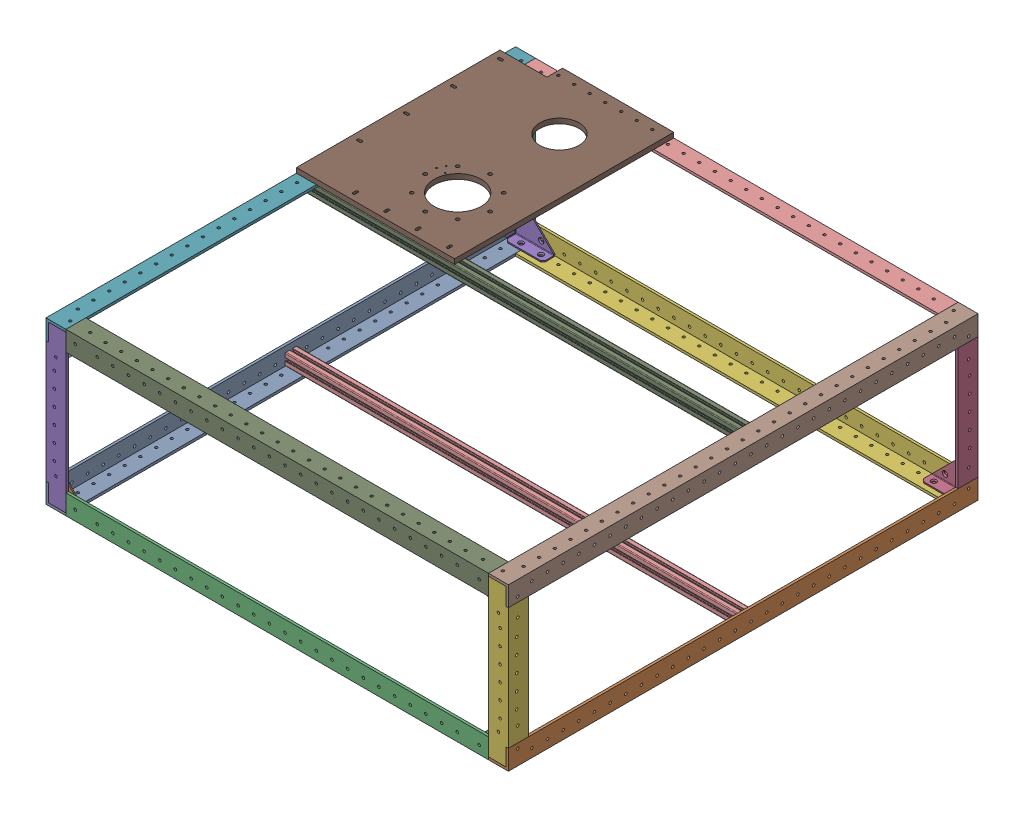
SolidWorks assembly URC Frame Assembly 2025-2023, configuration Default. Lengths in mm.
Overall size (590.8 212.69 600).
23 component instances, 6 part files, 91 mates.
Components (placement in the parent):
- 600mm L Angle 0.125 in-2023-2: 600mm L Angle 0.125 in-2023 [8982K421] at (-25.1001 123.5857 -689.9173) size (25.4 25.4 600)
- 600mm L Angle 0.125 in-2023-3: 600mm L Angle 0.125 in-2023 [8982K421] at (565.6999 123.5807 1148.4827) x (-1 0 0) z (0 0 -1) size (25.4 25.4 600)
- 200mm L Angle 0.125 in-2023-1: 200mm L Angle 0.125 in-2023 [8982K421] at (-25.1001 -892.4443 -70.7173) x (0 0 1) z (0 1 0) size (25.4 25.4 200)
- 200mm L Angle 0.125 in-2023-2: 200mm L Angle 0.125 in-2023 [8982K421] at (565.6999 1345.9557 -70.7173) x (0 0 1) z (0 -1 0) size (25.4 25.4 200)
- 200mm L Angle 0.125 in-2023-3: 200mm L Angle 0.125 in-2023 [8982K421] at (-25.1001 1345.9607 529.2827) x (0 0 -1) z (0 -1 0) size (25.4 25.4 200)
- 200mm L Angle 0.125 in-2023-4: 200mm L Angle 0.125 in-2023 [8982K421] at (565.6999 -892.4443 529.2827) x (0 0 -1) z (0 1 0) size (25.4 25.4 200)
- 600mm L Angle 0.125 in-2023-5: 600mm L Angle 0.125 in-2023 [8982K421] at (-25.1001 329.9257 -689.9173) x (0 -1 0) z (0 0 1) size (25.4 25.4 600)
- 600mm L Angle 0.125 in-2023-6: 600mm L Angle 0.125 in-2023 [8982K421] at (565.6999 329.9257 -689.9173) x (-1 0 0) z (0 0 1) size (25.4 25.4 600)
- 584 mm L Angle 0.125 in-2023-5: 584 mm L Angle 0.125 in-2023 [8982K421] at (-678.9001 329.9257 529.2827) x (0 -1 0) z (1 0 0) size (25.4 25.4 540)
- 584 mm L Angle 0.125 in-2023-6: 584 mm L Angle 0.125 in-2023 [8982K421] at (1219.4999 329.9257 -70.7173) x (0 -1 0) z (-1 0 0) size (25.4 25.4 540)
- 1088A31_Inside-Corner Reinforcing Bracket-2023-1: 1088A31_Inside-Corner Reinforcing Bracket-2023 [1088A31] at (562.5249 326.7507 524.5837) x (-1 0 0) z (0 -1 0) size (50.93 15.88 50.93)
- 1088A31_Inside-Corner Reinforcing Bracket-2023-2: 1088A31_Inside-Corner Reinforcing Bracket-2023 [1088A31] at (-21.9251 326.7507 524.5837) x (0 -1 0) z (1 0 0) size (50.93 15.88 50.93)
- 1088A31_Inside-Corner Reinforcing Bracket-2023-3: 1088A31_Inside-Corner Reinforcing Bracket-2023 [1088A31] at (562.5249 126.7557 524.5837) x (0 1 0) z (-1 0 0) size (50.93 15.88 50.93)
- 1088A31_Inside-Corner Reinforcing Bracket-2023-4: 1088A31_Inside-Corner Reinforcing Bracket-2023 [1088A31] at (-21.9251 126.7607 524.5837) x (1 0 0) z (0 1 0) size (50.93 15.88 50.93)
- 584 mm L Angle 0.125 in-2023-7: 584 mm L Angle 0.125 in-2023 [8982K421] at (1219.4999 123.5807 529.2827) x (0 1 0) z (-1 0 0) size (25.4 25.4 540)
- 1088A31_Inside-Corner Reinforcing Bracket-2023-5: 1088A31_Inside-Corner Reinforcing Bracket-2023 [1088A31] at (562.5249 126.7607 -66.0183) x (-1 0 0) z (0 1 0) size (50.93 15.88 50.93)
- 1088A31_Inside-Corner Reinforcing Bracket-2023-6: 1088A31_Inside-Corner Reinforcing Bracket-2023 [1088A31] at (-21.9251 126.7607 -66.0183) x (0 1 0) z (1 0 0) size (50.93 15.88 50.93)
- 584 mm L Angle 0.125 in-2023-9: 584 mm L Angle 0.125 in-2023 [8982K421] at (-678.9001 123.5857 -70.7173) x (0 1 0) z (1 0 0) size (25.4 25.4 540)
- 1088A31_Inside-Corner Reinforcing Bracket-2023-7: 1088A31_Inside-Corner Reinforcing Bracket-2023 [1088A31] at (562.5249 326.7507 -66.0183) x (0 -1 0) z (-1 0 0) size (50.93 15.88 50.93)
- 1088A31_Inside-Corner Reinforcing Bracket-2023-8: 1088A31_Inside-Corner Reinforcing Bracket-2023 [1088A31] at (-21.9251 326.7507 -66.0183) x (1 0 0) z (0 -1 0) size (50.93 15.88 50.93)
- T Slot Extrusion-2023-1: T Slot Extrusion-2023 [Default] at (92.5749 319.2507 199.2827) x (0 0 1) z (-1 0 0) size (15 15 584.45)
- T Slot Extrusion-2023-2: T Slot Extrusion-2023 [Default] at (92.5749 134.2607 219.2827) x (0 0 1) z (-1 0 0) size (15 15 584.45)
- 2025 Arm Plate-2023-1: 2025 Arm Plate-2023 [Default] at (105.8999 329.9257 69.2827) size (202 6.35 280)
Mates (geometry in assembly coordinates):
- Coincident10: coincident anti-aligned: plane of 600mm L Angle 0.125 in-2 through (0.2999 123.5857 529.2827) normal (1 0 0); plane of 584 mm L Angle 0.125 in-3 through (0.2999 123.5857 -70.7173) normal (-1 0 0)
- Coincident11: coincident aligned: plane of 600mm L Angle 0.125 in-2 through (0.2999 126.7607 529.2827) normal (0 1 0); plane of 584 mm L Angle 0.125 in-3 through (0.2999 126.7607 -45.3173) normal (0 1 0)
- Coincident12: coincident aligned: plane of 600mm L Angle 0.125 in-2 through (34.8999 148.9857 -70.7173) normal (0 0 -1); plane of 584 mm L Angle 0.125 in-3 through (0.2999 148.9857 -70.7173) normal (0 0 -1)
- Coincident16: coincident aligned: plane of 584 mm L Angle 0.125 in-3 through (0.2999 126.7607 -45.3173) normal (0 1 0); plane of 600mm L Angle 0.125 in-3 through (540.2999 126.7557 -70.7173) normal (0 1 0)
- Coincident17: coincident anti-aligned: plane of 584 mm L Angle 0.125 in-3 through (540.2999 148.9857 -10.7173) normal (1 0 0); plane of 600mm L Angle 0.125 in-3 through (540.2999 123.5807 -70.7173) normal (-1 0 0)
- Coincident18: coincident aligned: plane of 584 mm L Angle 0.125 in-3 through (0.2999 148.9857 -70.7173) normal (0 0 -1); plane of 600mm L Angle 0.125 in-3 through (565.6999 123.5807 -70.7173) normal (0 0 -1)
- Coincident19: coincident anti-aligned: plane of 600mm L Angle 0.125 in-3 through (540.2999 123.5807 -70.7173) normal (-1 0 0); plane of 584 mm L Angle 0.125 in-4 through (540.2999 123.5857 529.2827) normal (1 0 0)
- Coincident20: coincident aligned: plane of 600mm L Angle 0.125 in-3 through (540.2999 126.7557 -70.7173) normal (0 1 0); plane of 584 mm L Angle 0.125 in-4 through (540.2999 126.7607 503.8827) normal (0 1 0)
- Coincident21: coincident aligned: plane of 600mm L Angle 0.125 in-2 through (-25.1001 123.5857 529.2827) normal (0 0 1); plane of 584 mm L Angle 0.125 in-4 through (540.2999 148.9857 529.2827) normal (0 0 1)
- Coincident22: coincident aligned: plane of 600mm L Angle 0.125 in-2 through (-25.1001 148.9857 529.2827) normal (-1 0 0); plane of 200mm L Angle 0.125 in-1 through (-25.1001 326.7557 -70.7173) normal (-1 0 0)
- Coincident23: coincident aligned: plane of 584 mm L Angle 0.125 in-3 through (0.2999 148.9857 -70.7173) normal (0 0 -1); plane of 200mm L Angle 0.125 in-1 through (0.2999 326.7557 -70.7173) normal (0 0 -1)
- Coincident24: coincident anti-aligned: plane of 600mm L Angle 0.125 in-2 through (-21.9251 148.9857 529.2827) normal (0 1 0); plane of 200mm L Angle 0.125 in-1 through (11.8289 148.9857 -45.3173) normal (0 -1 0)
- Coincident25: coincident anti-aligned: plane of 600mm L Angle 0.125 in-3 through (540.2999 126.7557 -70.7173) normal (0 1 0); plane of 200mm L Angle 0.125 in-2 through (565.6999 126.7557 -70.7173) normal (0 -1 0)
- Coincident26: coincident aligned: plane of 584 mm L Angle 0.125 in-3 through (0.2999 148.9857 -70.7173) normal (0 0 -1); plane of 200mm L Angle 0.125 in-2 through (540.2999 126.7557 -70.7173) normal (0 0 -1)
- Coincident27: coincident aligned: plane of 600mm L Angle 0.125 in-3 through (565.6999 148.9807 -70.7173) normal (1 0 0); plane of 200mm L Angle 0.125 in-2 through (565.6999 126.7557 -70.7173) normal (1 0 0)
- Coincident28: coincident anti-aligned: plane of 600mm L Angle 0.125 in-2 through (0.2999 126.7607 529.2827) normal (0 1 0); plane of 200mm L Angle 0.125 in-3 through (-25.1001 126.7607 529.2827) normal (0 -1 0)
- Coincident29: coincident aligned: plane of 584 mm L Angle 0.125 in-4 through (540.2999 148.9857 529.2827) normal (0 0 1); plane of 200mm L Angle 0.125 in-3 through (0.2999 126.7607 529.2827) normal (0 0 1)
- Coincident30: coincident aligned: plane of 600mm L Angle 0.125 in-2 through (-25.1001 148.9857 529.2827) normal (-1 0 0); plane of 200mm L Angle 0.125 in-3 through (-25.1001 126.7607 529.2827) normal (-1 0 0)
- Coincident33: coincident anti-aligned: plane of 600mm L Angle 0.125 in-3 through (540.2999 126.7557 -70.7173) normal (0 1 0); plane of 200mm L Angle 0.125 in-4 through (540.2999 126.7557 469.2827) normal (0 -1 0)
- Coincident34: coincident aligned: plane of 584 mm L Angle 0.125 in-4 through (540.2999 148.9857 529.2827) normal (0 0 1); plane of 200mm L Angle 0.125 in-4 through (540.2999 326.7557 529.2827) normal (0 0 1)
- Coincident35: coincident aligned: plane of 600mm L Angle 0.125 in-3 through (565.6999 148.9807 -70.7173) normal (1 0 0); plane of 200mm L Angle 0.125 in-4 through (565.6999 326.7557 529.2827) normal (1 0 0)
- Coincident36: coincident aligned: plane of 200mm L Angle 0.125 in-3 through (-25.1001 126.7607 529.2827) normal (-1 0 0); plane of 600mm L Angle 0.125 in-4 through (-25.1001 129.9357 250.1294) normal (-1 0 0)
- Coincident37: coincident anti-aligned: plane of 600mm L Angle 0.125 in-2 through (0.2999 126.7607 529.2827) normal (0 1 0); plane of 600mm L Angle 0.125 in-4 through (-21.9251 126.7607 250.1294) normal (0 -1 0)
- Coincident39: coincident anti-aligned: plane of 200mm L Angle 0.125 in-1 through (11.8289 304.5257 -45.3173) normal (0 1 0); plane of 600mm L Angle 0.125 in-5 through (-25.1001 304.5257 529.2827) normal (0 -1 0)
- Coincident40: coincident aligned: plane of 200mm L Angle 0.125 in-1 through (0.2999 326.7557 -70.7173) normal (0 0 -1); plane of 600mm L Angle 0.125 in-5 through (0.2999 269.9257 -70.7173) normal (0 0 -1)
- Coincident41: coincident aligned: plane of 200mm L Angle 0.125 in-1 through (-25.1001 326.7557 -70.7173) normal (-1 0 0); plane of 600mm L Angle 0.125 in-5 through (-25.1001 329.9257 529.2827) normal (-1 0 0)
- Coincident42: coincident aligned: plane of 200mm L Angle 0.125 in-4 through (565.6999 326.7557 529.2827) normal (1 0 0); plane of 600mm L Angle 0.125 in-6 through (565.6999 304.5257 529.2827) normal (1 0 0)
- Coincident43: coincident anti-aligned: plane of 200mm L Angle 0.125 in-4 through (528.7709 304.5257 503.8827) normal (0 1 0); plane of 600mm L Angle 0.125 in-6 through (562.5249 304.5257 529.2827) normal (0 -1 0)
- Coincident44: coincident aligned: plane of 200mm L Angle 0.125 in-4 through (540.2999 326.7557 529.2827) normal (0 0 1); plane of 600mm L Angle 0.125 in-6 through (565.6999 329.9257 529.2827) normal (0 0 1)
- Coincident45: coincident anti-aligned: plane of 600mm L Angle 0.125 in-6 through (540.2999 329.9257 529.2827) normal (-1 0 0); plane of 584 mm L Angle 0.125 in-5 through (540.2999 329.9257 529.2827) normal (1 0 0)
- Coincident46: coincident aligned: plane of 200mm L Angle 0.125 in-4 through (540.2999 326.7557 529.2827) normal (0 0 1); plane of 584 mm L Angle 0.125 in-5 through (540.2999 329.9257 529.2827) normal (0 0 1)
- Coincident47: coincident aligned: plane of 600mm L Angle 0.125 in-6 through (565.6999 329.9257 529.2827) normal (0 1 0); plane of 584 mm L Angle 0.125 in-5 through (540.2999 329.9257 503.8827) normal (0 1 0)
- Coincident48: coincident aligned: plane of 200mm L Angle 0.125 in-2 through (540.2999 126.7557 -70.7173) normal (0 0 -1); plane of 584 mm L Angle 0.125 in-6 through (0.2999 329.9257 -70.7173) normal (0 0 -1)
- Coincident49: coincident aligned: plane of 600mm L Angle 0.125 in-6 through (565.6999 329.9257 529.2827) normal (0 1 0); plane of 584 mm L Angle 0.125 in-6 through (0.2999 329.9257 -45.3173) normal (0 1 0)
- Coincident50: coincident anti-aligned: plane of 600mm L Angle 0.125 in-5 through (0.2999 326.7507 529.2827) normal (1 0 0); plane of 584 mm L Angle 0.125 in-6 through (0.2999 329.9257 -70.7173) normal (-1 0 0)
- Concentric1: concentric aligned: circle of 600mm L Angle 0.125 in-6; circle of 1088A31_Inside-Corner Reinforcing Bracket-1
- Parallel2: parallel aligned: plane of 200mm L Angle 0.125 in-4 through (565.6999 326.7557 503.8827) normal (0 0 -1); plane of 1088A31_Inside-Corner Reinforcing Bracket-1 through (562.5249 325.2267 510.2327) normal (0 0 -1)
- Coincident52: coincident anti-aligned: plane of 200mm L Angle 0.125 in-4 through (562.5249 326.7557 503.8827) normal (-1 0 0); plane of 1088A31_Inside-Corner Reinforcing Bracket-1 through (562.5249 275.9507 524.5837) normal (1 0 0)
- Concentric2: concentric anti-aligned: circle of 600mm L Angle 0.125 in-5; circle of 1088A31_Inside-Corner Reinforcing Bracket-2
- Coincident53: coincident anti-aligned: plane of 200mm L Angle 0.125 in-3 through (-21.9251 126.7607 526.1077) normal (0 0 -1); plane of 1088A31_Inside-Corner Reinforcing Bracket-2 through (-20.4011 325.2267 526.1077) normal (0 0 1)
- Coincident54: coincident anti-aligned: plane of 600mm L Angle 0.125 in-5 through (-21.9251 304.5257 529.2827) normal (1 0 0); plane of 1088A31_Inside-Corner Reinforcing Bracket-2 through (-21.9251 275.9507 510.2327) normal (-1 0 0)
- Coincident55: coincident anti-aligned: plane of 200mm L Angle 0.125 in-4 through (562.5249 326.7557 503.8827) normal (-1 0 0); plane of 1088A31_Inside-Corner Reinforcing Bracket-3 through (562.5249 177.5557 510.2327) normal (1 0 0)
- Coincident56: coincident anti-aligned: plane of 200mm L Angle 0.125 in-4 through (562.5249 326.7557 526.1077) normal (0 0 -1); plane of 1088A31_Inside-Corner Reinforcing Bracket-3 through (561.0009 128.2797 526.1077) normal (0 0 1)
- Coincident57: coincident anti-aligned: plane of 600mm L Angle 0.125 in-3 through (540.2999 126.7557 -70.7173) normal (0 1 0); plane of 1088A31_Inside-Corner Reinforcing Bracket-3 through (511.7249 126.7557 524.5837) normal (0 -1 0)
- Coincident58: coincident anti-aligned: plane of 600mm L Angle 0.125 in-2 through (0.2999 126.7607 529.2827) normal (0 1 0); plane of 1088A31_Inside-Corner Reinforcing Bracket-4 through (28.8749 126.7607 510.2327) normal (0 -1 0)
- Coincident59: coincident anti-aligned: plane of 200mm L Angle 0.125 in-3 through (-21.9251 126.7607 526.1077) normal (0 0 -1); plane of 1088A31_Inside-Corner Reinforcing Bracket-4 through (-20.4011 128.2847 526.1077) normal (0 0 1)
- Coincident60: coincident anti-aligned: plane of 200mm L Angle 0.125 in-3 through (-21.9251 126.7607 503.8827) normal (1 0 0); plane of 1088A31_Inside-Corner Reinforcing Bracket-4 through (-21.9251 177.5607 524.5837) normal (-1 0 0)
- Coincident61: coincident aligned: plane of 600mm L Angle 0.125 in-3 through (565.6999 123.5807 -70.7173) normal (0 -1 0); plane of 584 mm L Angle 0.125 in-7 through (0.2999 123.5807 503.8827) normal (0 -1 0)
- Coincident62: coincident aligned: plane of 200mm L Angle 0.125 in-4 through (540.2999 326.7557 529.2827) normal (0 0 1); plane of 584 mm L Angle 0.125 in-7 through (0.2999 123.5807 529.2827) normal (0 0 1)
- Coincident64: coincident anti-aligned: plane of 600mm L Angle 0.125 in-3 through (540.2999 123.5807 -70.7173) normal (-1 0 0); plane of 584 mm L Angle 0.125 in-7 through (540.2999 183.5807 503.8827) normal (1 0 0)
- Coincident65: coincident aligned: plane of 200mm L Angle 0.125 in-2 through (540.2999 126.7557 -70.7173) normal (0 0 -1); plane of 600mm L Angle 0.125 in-6 through (505.6999 304.5257 -70.7173) normal (0 0 -1)
- Coincident66: coincident: plane of 584 mm L Angle 0.125 in-3 through (0.2999 126.7607 -45.3173) normal (0 1 0); plane of 1088A31_Inside-Corner Reinforcing Bracket-5 through (511.7249 126.7607 -51.6673) normal (0 -1 0)
- Coincident67: coincident: plane of 584 mm L Angle 0.125 in-3 through (0.2999 126.7607 -67.5423) normal (0 0 1); plane of 1088A31_Inside-Corner Reinforcing Bracket-5 through (561.0009 128.2847 -67.5423) normal (0 0 -1)
- Coincident68: coincident anti-aligned: plane of 200mm L Angle 0.125 in-2 through (562.5249 126.7557 -45.3173) normal (-1 0 0); plane of 1088A31_Inside-Corner Reinforcing Bracket-5 through (562.5249 177.5607 -66.0183) normal (1 0 0)
- Parallel3: parallel anti-aligned: plane of 584 mm L Angle 0.125 in-7 through (0.2999 126.7557 503.8827) normal (0 0 -1); plane of 584 mm L Angle 0.125 in-8 through (0.2999 123.5857 -45.3173) normal (0 0 1)
- Coincident70: coincident aligned: plane of 600mm L Angle 0.125 in-2 through (-25.1001 123.5857 529.2827) normal (0 -1 0); plane of 584 mm L Angle 0.125 in-8 through (0.2999 123.5857 -70.7173) normal (0 -1 0)
- Coincident71: coincident aligned: plane of 200mm L Angle 0.125 in-1 through (0.2999 326.7557 -70.7173) normal (0 0 -1); plane of 584 mm L Angle 0.125 in-8 through (0.2999 148.9857 -70.7173) normal (0 0 -1)
- Coincident72: coincident anti-aligned: plane of 200mm L Angle 0.125 in-1 through (0.2999 326.7557 -67.5423) normal (1 0 0); plane of 584 mm L Angle 0.125 in-8 through (0.2999 123.5857 -70.7173) normal (-1 0 0)
- Coincident73: coincident anti-aligned: plane of 1088A31_Inside-Corner Reinforcing Bracket-5 through (561.0009 128.2847 -67.5423) normal (0 0 -1); plane of 584 mm L Angle 0.125 in-8 through (0.2999 126.7607 -67.5423) normal (0 0 1)
- Coincident74: coincident aligned: plane of 200mm L Angle 0.125 in-2 through (540.2999 126.7557 -70.7173) normal (0 0 -1); plane of 584 mm L Angle 0.125 in-8 through (0.2999 148.9857 -70.7173) normal (0 0 -1)
- Coincident75: coincident aligned: plane of 600mm L Angle 0.125 in-3 through (565.6999 123.5807 -70.7173) normal (0 0 -1); plane of 584 mm L Angle 0.125 in-8 through (0.2999 148.9857 -70.7173) normal (0 0 -1)
- Coincident76: coincident aligned: plane of 600mm L Angle 0.125 in-2 through (34.8999 148.9857 -70.7173) normal (0 0 -1); plane of 584 mm L Angle 0.125 in-8 through (0.2999 148.9857 -70.7173) normal (0 0 -1)
- Coincident77: coincident aligned: plane of 600mm L Angle 0.125 in-5 through (0.2999 329.9257 529.2827) normal (0 1 0); plane of 584 mm L Angle 0.125 in-6 through (0.2999 329.9257 -45.3173) normal (0 1 0)
- Coincident78: coincident anti-aligned: plane of 600mm L Angle 0.125 in-5 through (0.2999 326.7507 529.2827) normal (1 0 0); plane of 584 mm L Angle 0.125 in-5 through (0.2999 269.9257 503.8827) normal (-1 0 0)
- Coincident79: coincident anti-aligned: plane of 200mm L Angle 0.125 in-1 through (-21.9251 326.7557 -67.5423) normal (0 0 1); plane of 1088A31_Inside-Corner Reinforcing Bracket-6 through (-20.4011 128.2847 -67.5423) normal (0 0 -1)
- Coincident80: coincident anti-aligned: plane of 200mm L Angle 0.125 in-1 through (-21.9251 326.7557 -45.3173) normal (1 0 0); plane of 1088A31_Inside-Corner Reinforcing Bracket-6 through (-21.9251 177.5607 -51.6673) normal (-1 0 0)
- Coincident81: coincident anti-aligned: plane of 584 mm L Angle 0.125 in-8 through (0.2999 126.7607 -45.3173) normal (0 1 0); plane of 1088A31_Inside-Corner Reinforcing Bracket-6 through (28.8749 126.7607 -66.0183) normal (0 -1 0)
- Coincident82: coincident aligned: plane of 600mm L Angle 0.125 in-2 through (0.2999 126.7607 529.2827) normal (0 1 0); plane of 584 mm L Angle 0.125 in-9 through (540.2999 126.7607 -67.5423) normal (0 1 0)
- Coincident83: coincident anti-aligned: plane of 1088A31_Inside-Corner Reinforcing Bracket-6 through (-20.4011 128.2847 -67.5423) normal (0 0 -1); plane of 584 mm L Angle 0.125 in-9 through (540.2999 148.9857 -67.5423) normal (0 0 1)
- Coincident84: coincident anti-aligned: plane of 600mm L Angle 0.125 in-3 through (540.2999 123.5807 -70.7173) normal (-1 0 0); plane of 584 mm L Angle 0.125 in-9 through (540.2999 123.5857 -70.7173) normal (1 0 0)
- Coincident85: coincident anti-aligned: plane of 1088A31_Inside-Corner Reinforcing Bracket-5 through (511.7249 126.7607 -51.6673) normal (0 -1 0); plane of 584 mm L Angle 0.125 in-9 through (540.2999 126.7607 -67.5423) normal (0 1 0)
- Coincident86: coincident anti-aligned: plane of 1088A31_Inside-Corner Reinforcing Bracket-5 through (561.0009 128.2847 -67.5423) normal (0 0 -1); plane of 584 mm L Angle 0.125 in-9 through (540.2999 148.9857 -67.5423) normal (0 0 1)
- Coincident87: coincident anti-aligned: plane of 200mm L Angle 0.125 in-2 through (562.5249 126.7557 -67.5423) normal (0 0 1); plane of 1088A31_Inside-Corner Reinforcing Bracket-5 through (561.0009 128.2847 -67.5423) normal (0 0 -1)
- Coincident88: coincident aligned: plane of 600mm L Angle 0.125 in-3 through (565.6999 123.5807 -70.7173) normal (0 0 -1); plane of 200mm L Angle 0.125 in-2 through (540.2999 126.7557 -70.7173) normal (0 0 -1)
- Coincident89: coincident aligned: plane of 600mm L Angle 0.125 in-2 through (-25.1001 123.5857 529.2827) normal (0 0 1); plane of 200mm L Angle 0.125 in-3 through (0.2999 126.7607 529.2827) normal (0 0 1)
- Coincident90: coincident anti-aligned: plane of 584 mm L Angle 0.125 in-6 through (0.2999 326.7507 -67.5423) normal (0 -1 0); plane of 1088A31_Inside-Corner Reinforcing Bracket-7 through (511.7249 326.7507 -66.0183) normal (0 1 0)
- Coincident91: coincident anti-aligned: plane of 584 mm L Angle 0.125 in-6 through (0.2999 304.5257 -67.5423) normal (0 0 1); plane of 1088A31_Inside-Corner Reinforcing Bracket-7 through (561.0009 325.2267 -67.5423) normal (0 0 -1)
- Coincident92: coincident anti-aligned: plane of 600mm L Angle 0.125 in-6 through (562.5249 326.7507 529.2827) normal (-1 0 0); plane of 1088A31_Inside-Corner Reinforcing Bracket-7 through (562.5249 275.9507 -51.6673) normal (1 0 0)
- Coincident93: coincident anti-aligned: plane of 200mm L Angle 0.125 in-1 through (-21.9251 326.7557 -67.5423) normal (0 0 1); plane of 1088A31_Inside-Corner Reinforcing Bracket-8 through (-20.4011 325.2267 -67.5423) normal (0 0 -1)
- Coincident94: coincident anti-aligned: plane of 200mm L Angle 0.125 in-1 through (-21.9251 326.7557 -45.3173) normal (1 0 0); plane of 1088A31_Inside-Corner Reinforcing Bracket-8 through (-21.9251 275.9507 -66.0183) normal (-1 0 0)
- Coincident95: coincident anti-aligned: plane of 584 mm L Angle 0.125 in-6 through (0.2999 326.7507 -67.5423) normal (0 -1 0); plane of 1088A31_Inside-Corner Reinforcing Bracket-8 through (28.8749 326.7507 -51.6673) normal (0 1 0)
- Coincident96: coincident anti-aligned: plane of 600mm L Angle 0.125 in-2 through (0.2999 126.7607 529.2827) normal (0 1 0); plane of 1088A31_Inside-Corner Reinforcing Bracket-6 through (28.8749 126.7607 -66.0183) normal (0 -1 0)
- Coincident97: coincident anti-aligned: plane of 600mm L Angle 0.125 in-5 through (-21.9251 304.5257 529.2827) normal (1 0 0); plane of T Slot Extrusion-1 through (-21.9251 325.7507 192.7827) normal (-1 0 0)
- Parallel4: parallel aligned: plane of 600mm L Angle 0.125 in-5 through (0.2999 329.9257 529.2827) normal (0 1 0); plane of T Slot Extrusion-1 through (562.5249 326.7507 197.2827) normal (0 1 0)
- Coincident99: coincident anti-aligned: plane of 600mm L Angle 0.125 in-2 through (-21.9251 126.7607 529.2827) normal (1 0 0); plane of T Slot Extrusion-2 through (-21.9251 140.7607 212.7827) normal (-1 0 0)
- Parallel5: parallel aligned: plane of 600mm L Angle 0.125 in-2 through (-21.9251 148.9857 529.2827) normal (0 1 0); plane of T Slot Extrusion-2 through (562.5249 141.7607 225.7827) normal (0 1 0)
- Concentric8: concentric anti-aligned: circle of 600mm L Angle 0.125 in-2; circle of T Slot Extrusion-2
- Concentric9: concentric aligned: circle of 584 mm L Angle 0.125 in-6; circle of 2025 Arm Plate-1
- Concentric10: concentric aligned: circle of 584 mm L Angle 0.125 in-6; circle of 2025 Arm Plate-1
- Coincident102: coincident anti-aligned: plane of 600mm L Angle 0.125 in-5 through (0.2999 329.9257 529.2827) normal (0 1 0); plane of 2025 Arm Plate-1 through (105.8999 329.9257 69.2827) normal (0 -1 0)
- Concentric11: concentric aligned: circle of 600mm L Angle 0.125 in-6; circle of T Slot Extrusion-1
